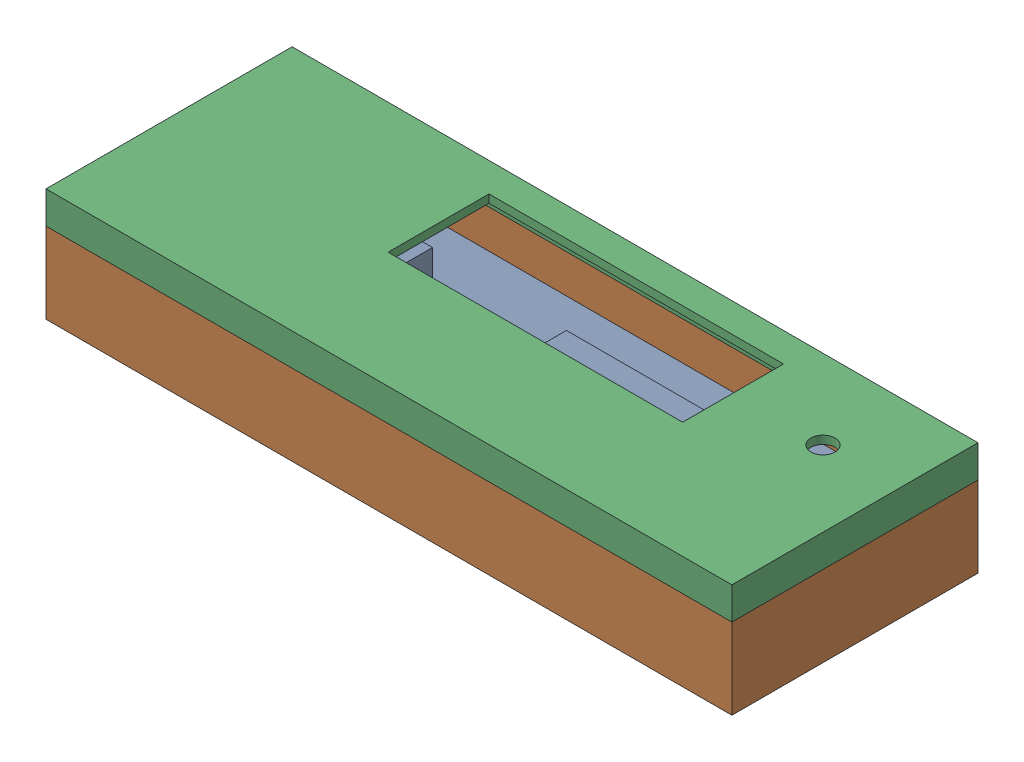
SolidWorks assembly Profhacks Case, configuration Default. Lengths in mm.
Overall size (170 28 61).
3 component instances, 3 part files, 6 mates.
Components (placement in the parent):
- Breadboard-1: Breadboard [Default] at (-66.1982 28.3442 92.094) size (164 18.1 54)
- Bottom Case-1: Bottom Case [Default] at (-69.1982 26.3442 96.094) size (170 26 61)
- Top Case-1: Top Case [Default] at (100.8018 46.3442 35.094) x (-1 0 0) z (0 0 -1) size (170 8 61)
Mates (geometry in assembly coordinates):
- Coincident1: coincident anti-aligned: plane of Breadboard-1 through (-66.1982 28.3442 92.094) normal (0 -1 0); plane of Bottom Case-1 through (-69.1982 28.3442 96.094) normal (0 1 0)
- Distance1: distance = 1 mm anti-aligned: plane of Breadboard-1 through (-66.1982 37.8442 38.094) normal (0 0 -1); plane of Bottom Case-1 through (-67.1982 28.3442 37.094) normal (0 0 1)
- Distance2: distance = 1 mm anti-aligned: plane of Breadboard-1 through (-66.1982 37.8442 92.094) normal (-1 0 0); plane of Bottom Case-1 through (-67.1982 28.3442 94.094) normal (1 0 0)
- Coincident11: coincident aligned: plane of Bottom Case-1 through (100.8018 46.3442 96.094) normal (1 0 0); plane of Top Case-1 through (100.8018 54.3442 35.094) normal (1 0 0)
- Coincident12: coincident anti-aligned: plane of Bottom Case-1 through (-69.1982 46.3442 96.094) normal (0 1 0); plane of Top Case-1 through (100.8018 46.3442 35.094) normal (0 -1 0)
- Coincident13: coincident aligned: plane of Bottom Case-1 through (-69.1982 46.3442 35.094) normal (0 0 -1); plane of Top Case-1 through (12.8018 54.3442 35.094) normal (0 0 -1)
